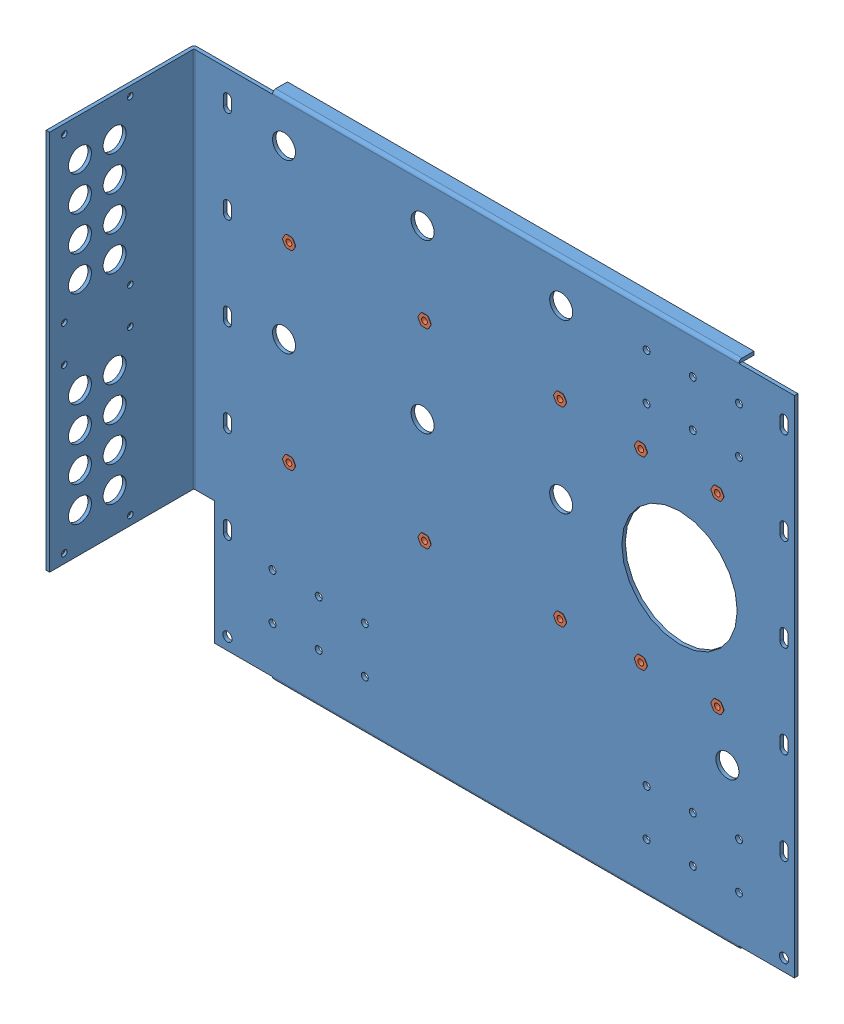
SolidWorks assembly PABasePlate, configuration Default. Lengths in mm.
Overall size (525 442.27 138).
19 component instances, 3 part files, 32 mates.
Components (placement in the parent):
- PA_Plate_F-1: PA_Plate_F [Default] at origin size (523 442.27 138)
- INSERT M6_EX_F-1: INSERT M6_EX_F [Default] at (-173.625 -84.332 3) x (0.866025 -0.5 0) z (-0.5 -0.866025 0) size (10 12.4 10.93)
- INSERT M6_EX_F-2: INSERT M6_EX_F [Default] at (-37.35 -86.822 3) x (0.866025 -0.5 0) z (-0.5 -0.866025 0) size (10 12.4 10.93)
- INSERT M6_EX_F-3: INSERT M6_EX_F [Default] at (-408.325 -249.332 3) x (0.866025 -0.5 0) z (-0.5 -0.866025 0) size (10 12.4 10.93)
- INSERT M6_EX_F-4: INSERT M6_EX_F [Default] at (-408.325 -84.332 3) x (-0.866025 0.5 0) z (0.5 0.866025 0) size (10 12.4 10.93)
- INSERT M6_EX_F-5: INSERT M6_EX_F [Default] at (-173.625 -249.332 3) x (0.866025 -0.5 0) z (-0.5 -0.866025 0) size (10 12.4 10.93)
- INSERT M6_EX_F-6: INSERT M6_EX_F [Default] at (-103.65 -86.822 3) x (0.866025 -0.5 0) z (-0.5 -0.866025 0) size (10 12.4 10.93)
- INSERT M6_EX_F-7: INSERT M6_EX_F [Default] at (-37.35 -246.842 3) x (0.866025 -0.5 0) z (-0.5 -0.866025 0) size (10 12.4 10.93)
- INSERT M6_EX_F-8: INSERT M6_EX_F [Default] at (-103.65 -246.842 3) x (0.866025 -0.5 0) z (-0.5 -0.866025 0) size (10 12.4 10.93)
- INSERT M6_EX_F-10: INSERT M6_EX_F [Default] at (-290.975 -84.332 3) x (0.866025 -0.5 0) z (-0.5 -0.866025 0) size (10 12.4 10.93)
- INSERT M6_EX_F-12: INSERT M6_EX_F [Default] at (-290.975 -249.332 3) x (0.866025 -0.5 0) z (-0.5 -0.866025 0) size (10 12.4 10.93)
- CLS-M4-0-PennEngineering-01-13-2017_F-13: CLS-M4-0-PennEngineering-01-13-2017_F [Default] at (-493.23 -161.4004 115.3) x (-1 0 0) z (0 0 1) size (2.77 7.87 7.87)
- CLS-M4-0-PennEngineering-01-13-2017_F-12: CLS-M4-0-PennEngineering-01-13-2017_F [Default] at (-493.23 -302.6752 115.3) x (-1 0 0) z (0 0 1) size (2.77 7.87 7.87)
- CLS-M4-0-PennEngineering-01-13-2017_F-10: CLS-M4-0-PennEngineering-01-13-2017_F [Default] at (-493.23 -161.4004 58.15) x (-1 0 0) z (0 0 1) size (2.77 7.87 7.87)
- CLS-M4-0-PennEngineering-01-13-2017_F-9: CLS-M4-0-PennEngineering-01-13-2017_F [Default] at (-493.23 -302.6752 58.15) x (-1 0 0) z (0 0 1) size (2.77 7.87 7.87)
- CLS-M4-0-PennEngineering-01-13-2017_F-14: CLS-M4-0-PennEngineering-01-13-2017_F [Default] at (-493.23 11.4752 58.15) x (-1 0 0) z (0 0 1) size (2.77 7.87 7.87)
- CLS-M4-0-PennEngineering-01-13-2017_F-16: CLS-M4-0-PennEngineering-01-13-2017_F [Default] at (-493.23 11.4752 115.3) x (-1 0 0) z (0 0 1) size (2.77 7.87 7.87)
- CLS-M4-0-PennEngineering-01-13-2017_F-11: CLS-M4-0-PennEngineering-01-13-2017_F [Default] at (-493.23 -129.7996 115.3) x (-1 0 0) z (0 0 1) size (2.77 7.87 7.87)
- CLS-M4-0-PennEngineering-01-13-2017_F-15: CLS-M4-0-PennEngineering-01-13-2017_F [Default] at (-493.23 -129.7996 58.15) x (-1 0 0) z (0 0 1) size (2.77 7.87 7.87)
Mates (geometry in assembly coordinates):
- Coincident11: coincident anti-aligned: plane of PA_Plate_F-1 through (-465 -569 3) normal (0 0 1); plane of INSERT M6_EX_F-4 through (-408.325 -84.332 3) normal (0 0 -1)
- Coincident1: coincident aligned: plane of INSERT M6_EX_F-1 through (-173.625 -84.332 -9) normal (0 0 -1); plane of INSERT M6_EX_F-6 through (-103.65 -86.822 -9) normal (0 0 -1)
- Coincident5: coincident aligned: plane of INSERT M6_EX_F-1 through (-173.625 -84.332 -9) normal (0 0 -1); plane of INSERT M6_EX_F-4 through (-408.325 -84.332 -9) normal (0 0 -1)
- Coincident6: coincident aligned: plane of INSERT M6_EX_F-1 through (-173.625 -84.332 -9) normal (0 0 -1); plane of INSERT M6_EX_F-6 through (-103.65 -86.822 -9) normal (0 0 -1)
- Coincident3: coincident aligned: plane of INSERT M6_EX_F-2 through (-37.35 -86.822 -9) normal (0 0 -1); plane of INSERT M6_EX_F-6 through (-103.65 -86.822 -9) normal (0 0 -1)
- Coincident4: coincident aligned: plane of INSERT M6_EX_F-3 through (-408.325 -249.332 -9) normal (0 0 -1); plane of INSERT M6_EX_F-4 through (-408.325 -84.332 -9) normal (0 0 -1)
- Coincident10: coincident aligned: plane of INSERT M6_EX_F-3 through (-408.325 -249.332 -9) normal (0 0 -1); plane of INSERT M6_EX_F-5 through (-173.625 -249.332 -9) normal (0 0 -1)
- Coincident7: coincident aligned: plane of INSERT M6_EX_F-6 through (-103.65 -86.822 -9) normal (0 0 -1); plane of INSERT M6_EX_F-7 through (-37.35 -246.842 -9) normal (0 0 -1)
- Coincident12: coincident aligned: plane of INSERT M6_EX_F-8 through (-103.65 -246.842 -9) normal (0 0 -1); plane of INSERT M6_EX_F-5 through (-173.625 -249.332 -9) normal (0 0 -1)
- Coincident13: coincident aligned: plane of INSERT M6_EX_F-8 through (-103.65 -246.842 -9) normal (0 0 -1); plane of INSERT M6_EX_F-7 through (-37.35 -246.842 -9) normal (0 0 -1)
- Coincident14: coincident aligned: plane of INSERT M6_EX_F-10 through (-290.975 -84.332 -9) normal (0 0 -1); plane of INSERT M6_EX_F-12 through (-290.975 -249.332 -9) normal (0 0 -1)
- Coincident16: coincident aligned: plane of INSERT M6_EX_F-3 through (-408.325 -249.332 -9) normal (0 0 -1); plane of INSERT M6_EX_F-12 through (-290.975 -249.332 -9) normal (0 0 -1)
- Width1: width anti-aligned: plane of PA_Plate_F-1 through (-296.2866 -249.332 -10) normal (0.866025 0.5 0); plane of PA_Plate_F-1 through (-285.6634 -249.332 -10) normal (-0.866025 -0.5 0); plane of INSERT M6_EX_F-12 through (-293.5731 -253.832 3) normal (-0.866025 -0.5 0); plane of INSERT M6_EX_F-12 through (-288.3769 -244.832 3) normal (0.866025 0.5 0)
- Width2: width anti-aligned: plane of PA_Plate_F-1 through (-296.2866 -84.332 -10) normal (0.866025 0.5 0); plane of PA_Plate_F-1 through (-285.6634 -84.332 -10) normal (-0.866025 -0.5 0); plane of INSERT M6_EX_F-10 through (-293.5731 -88.832 3) normal (-0.866025 -0.5 0); plane of INSERT M6_EX_F-10 through (-288.3769 -79.832 3) normal (0.866025 0.5 0)
- Width3: width anti-aligned: plane of PA_Plate_F-1 through (-293.6308 -244.732 -10) normal (0.866025 -0.5 0); plane of PA_Plate_F-1 through (-288.3192 -253.932 -10) normal (-0.866025 0.5 0); plane of INSERT M6_EX_F-12 through (-296.1712 -249.332 3) normal (-0.866025 0.5 0); plane of INSERT M6_EX_F-12 through (-285.7788 -249.332 3) normal (0.866025 -0.5 0)
- Width4: width anti-aligned: plane of PA_Plate_F-1 through (-293.6308 -79.732 -10) normal (0.866025 -0.5 0); plane of PA_Plate_F-1 through (-288.3192 -88.932 -10) normal (-0.866025 0.5 0); plane of INSERT M6_EX_F-10 through (-296.1712 -84.332 3) normal (-0.866025 0.5 0); plane of INSERT M6_EX_F-10 through (-285.7788 -84.332 3) normal (0.866025 -0.5 0)
- Coincident17: coincident anti-aligned: plane of PA_Plate_F-1 through (-494 19.4 -351.9782) normal (-1 0 0); plane of CLS-M4-0-PennEngineering-01-13-2017_F-16 through (-494 11.4752 117.2675) normal (1 0 0)
- Coincident18: coincident aligned: plane of CLS-M4-0-PennEngineering-01-13-2017_F-14 through (-494 11.4752 60.1175) normal (1 0 0); plane of CLS-M4-0-PennEngineering-01-13-2017_F-16 through (-494 11.4752 117.2675) normal (1 0 0)
- Coincident19: coincident aligned: plane of CLS-M4-0-PennEngineering-01-13-2017_F-16 through (-494 11.4752 117.2675) normal (1 0 0); plane of CLS-M4-0-PennEngineering-01-13-2017_F-11 through (-494 -129.7996 117.2675) normal (1 0 0)
- Coincident20: coincident aligned: plane of CLS-M4-0-PennEngineering-01-13-2017_F-16 through (-494 11.4752 117.2675) normal (1 0 0); plane of CLS-M4-0-PennEngineering-01-13-2017_F-15 through (-494 -129.7996 60.1175) normal (1 0 0)
- Coincident21: coincident aligned: plane of CLS-M4-0-PennEngineering-01-13-2017_F-13 through (-494 -161.4004 117.2675) normal (1 0 0); plane of CLS-M4-0-PennEngineering-01-13-2017_F-16 through (-494 11.4752 117.2675) normal (1 0 0)
- Coincident22: coincident aligned: plane of CLS-M4-0-PennEngineering-01-13-2017_F-10 through (-494 -161.4004 60.1175) normal (1 0 0); plane of CLS-M4-0-PennEngineering-01-13-2017_F-16 through (-494 11.4752 117.2675) normal (1 0 0)
- Coincident23: coincident aligned: plane of CLS-M4-0-PennEngineering-01-13-2017_F-12 through (-494 -302.6752 117.2675) normal (1 0 0); plane of CLS-M4-0-PennEngineering-01-13-2017_F-16 through (-494 11.4752 117.2675) normal (1 0 0)
- Coincident24: coincident aligned: plane of CLS-M4-0-PennEngineering-01-13-2017_F-9 through (-494 -302.6752 60.1175) normal (1 0 0); plane of CLS-M4-0-PennEngineering-01-13-2017_F-16 through (-494 11.4752 117.2675) normal (1 0 0)
- Concentric1: concentric anti-aligned: cylinder of PA_Plate_F-1 through (-494 11.4752 115.3) axis (1 0 0) radius 2.5; cylinder of CLS-M4-0-PennEngineering-01-13-2017_F-16 through (-494.882 11.4752 115.3) axis (-1 0 0) radius 3.935
- Concentric2: concentric anti-aligned: cylinder of PA_Plate_F-1 through (-494 11.4752 58.15) axis (1 0 0) radius 2.5; cylinder of CLS-M4-0-PennEngineering-01-13-2017_F-14 through (-494.882 11.4752 58.15) axis (-1 0 0) radius 3.935
- Concentric3: concentric anti-aligned: cylinder of PA_Plate_F-1 through (-494 -129.7996 115.3) axis (1 0 0) radius 2.5; cylinder of CLS-M4-0-PennEngineering-01-13-2017_F-11 through (-494.882 -129.7996 115.3) axis (-1 0 0) radius 3.935
- Concentric4: concentric anti-aligned: cylinder of PA_Plate_F-1 through (-494 -129.7996 58.15) axis (1 0 0) radius 2.5; cylinder of CLS-M4-0-PennEngineering-01-13-2017_F-15 through (-494.882 -129.7996 58.15) axis (-1 0 0) radius 3.935
- Concentric5: concentric anti-aligned: cylinder of PA_Plate_F-1 through (-494 -161.4004 115.3) axis (1 0 0) radius 2.5; cylinder of CLS-M4-0-PennEngineering-01-13-2017_F-13 through (-494.882 -161.4004 115.3) axis (-1 0 0) radius 3.935
- Concentric6: concentric anti-aligned: cylinder of PA_Plate_F-1 through (-494 -161.4004 58.15) axis (1 0 0) radius 2.5; cylinder of CLS-M4-0-PennEngineering-01-13-2017_F-10 through (-494.882 -161.4004 58.15) axis (-1 0 0) radius 3.935
- Concentric7: concentric anti-aligned: cylinder of PA_Plate_F-1 through (-494 -302.6752 115.3) axis (1 0 0) radius 2.5; cylinder of CLS-M4-0-PennEngineering-01-13-2017_F-12 through (-494.882 -302.6752 115.3) axis (-1 0 0) radius 3.935
- Concentric8: concentric anti-aligned: cylinder of PA_Plate_F-1 through (-494 -302.6752 58.15) axis (1 0 0) radius 2.5; cylinder of CLS-M4-0-PennEngineering-01-13-2017_F-9 through (-494.882 -302.6752 58.15) axis (-1 0 0) radius 3.935
